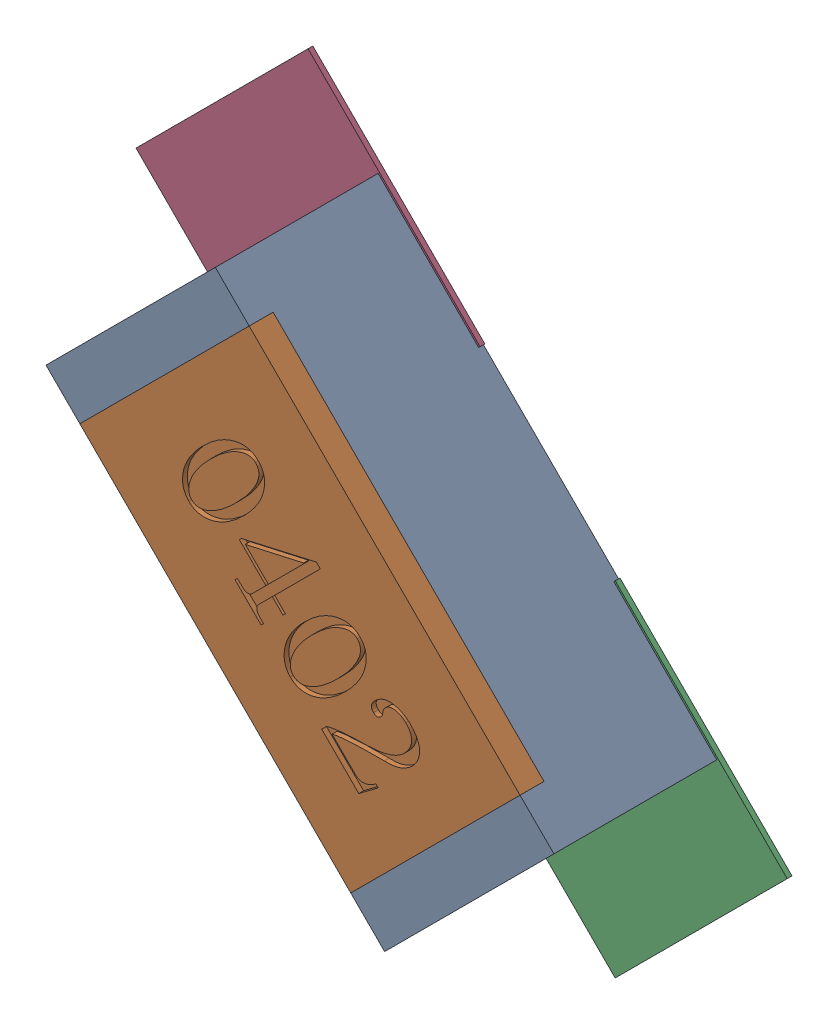
SolidWorks assembly R121, configuration Défaut. Lengths in mm.
Overall size (1.36 1.36 0.35).
5 component instances, 2 part files, 0 mates.
Components (placement in the parent):
- R0402-1: R0402 [Défaut] at (74.2919 -17.02 0) x (0.707107 -0.707107 0) z (0 0 1) size (1 0.5 0.35)
- 8260096304-1: 8260096304 [Défaut] at (74.6101 -17.3381 0) size (0.72 0.72 0.01)
  - Extruded_694-1: Extruded_694 [Défaut] at origin size (0.72 0.72 0.01)
- 8260096304-2: 8260096304 [Défaut] at (73.9688 -16.6967 0) size (0.72 0.72 0.01)
  - Extruded_694-1: Extruded_694 [Défaut] at origin size (0.72 0.72 0.01)
